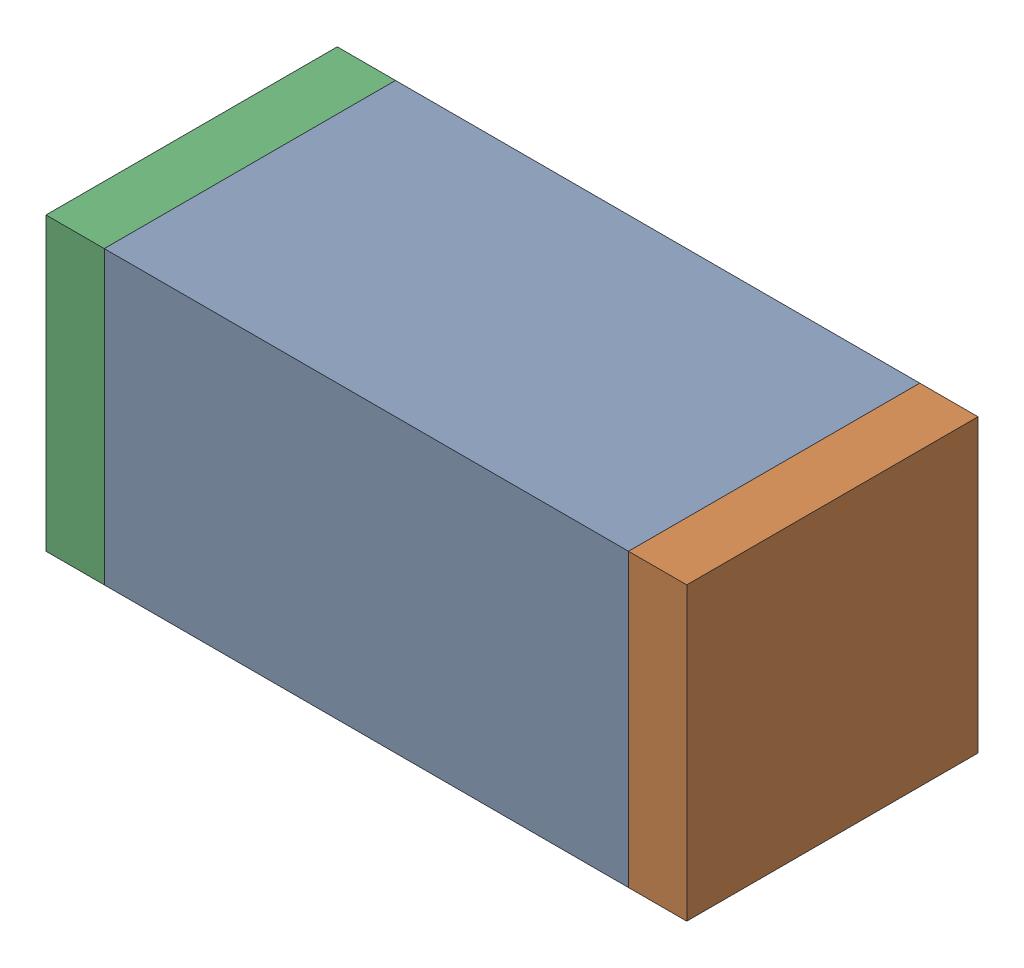
SolidWorks assembly C38, configuration Default. Lengths in mm.
Overall size (1.1 0.5 0.5).
6 component instances, 2 part files, 0 mates.
Components (placement in the parent):
- 836749680-1: 836749680 [Default] at (133.55 32.6 0) size (0.9 0.5 0.5)
  - Extruded_4-1: Extruded_4 [Default] at origin size (0.9 0.5 0.5)
- 810156080-1: 810156080 [Default] at (134.05 32.6 0) size (0.1 0.5 0.5)
  - Extruded_5-1: Extruded_5 [Default] at origin size (0.1 0.5 0.5)
- 810156080-2: 810156080 [Default] at (133.05 32.6 0) size (0.1 0.5 0.5)
  - Extruded_5-1: Extruded_5 [Default] at origin size (0.1 0.5 0.5)
